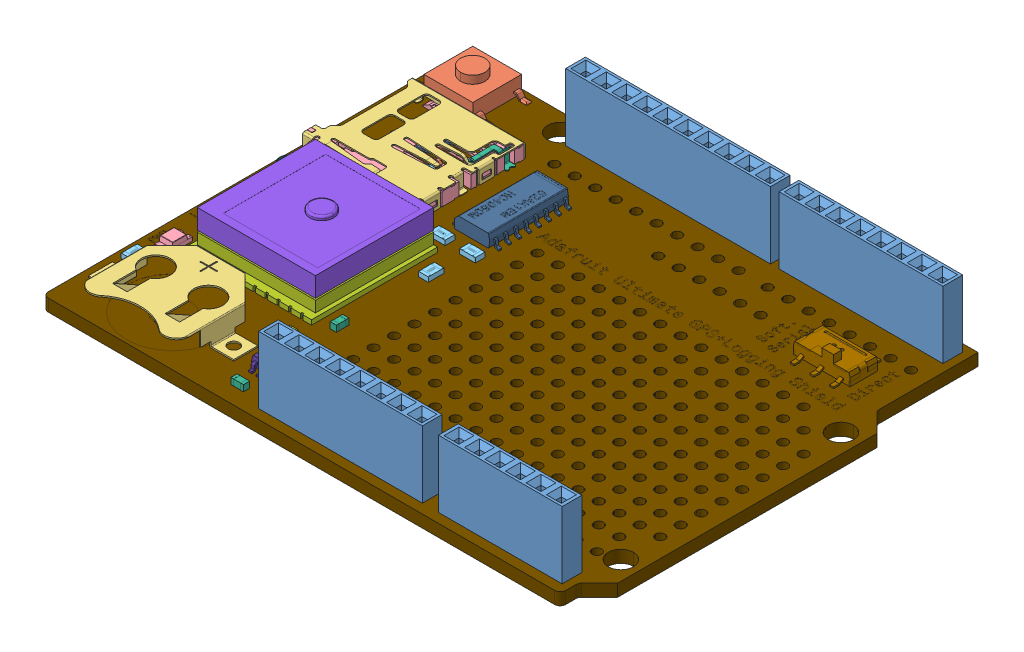
SolidWorks assembly Adafruit Ultimate GPS Logger Shield.stp, configuration Défaut. Lengths in mm.
Overall size (68.2 11.7 53.05).
43 component instances, 25 part files, 0 mates.
Components (placement in the parent):
- microSD_Connector.stp-1: microSD_Connector.stp [Défaut] at (-28.4341 1.764 56.1048) x (0 0 -1) z (1 0 0) size (14.11 1.91 15.46)
  - microSD_Pin_11.35.stp-1: microSD_Pin_11.35.stp [Défaut] at (1.325 0 -2) x (0 0 1) z (-1 0 0) size (7.35 1.15 0.63)
  - microSD_Pin_11.15.stp-1: microSD_Pin_11.15.stp [Défaut] at (2.425 0 -2) x (0 0 1) z (-1 0 0) size (7.35 1.15 0.62)
  - microSD_Pin_11.15.stp-2: microSD_Pin_11.15.stp [Défaut] at (-1.975 0 -2) x (0 0 1) z (-1 0 0) size (7.35 1.15 0.62)
  - microSD_Cover.stp-1: microSD_Cover.stp [Défaut] at (0 1.7 0) x (1 0 0) z (0 0 -1) size (13.96 1.91 15.21)
  - microSD_Pin_11.35.stp-2: microSD_Pin_11.35.stp [Défaut] at (3.525 0 -2) x (0 0 1) z (-1 0 0) size (7.35 1.15 0.63)
  - microSD_Body.stp-1: microSD_Body.stp [Défaut] at origin size (14.1 1.85 15.2)
  - microSD_Pin_10.75.stp-1: microSD_Pin_10.75.stp [Défaut] at (-0.875 0 -2) x (0 0 1) z (-1 0 0) size (7.25 1.15 0.62)
  - microSD_Pin_11.15.stp-3: microSD_Pin_11.15.stp [Défaut] at (4.625 0 -2) x (0 0 1) z (-1 0 0) size (7.35 1.15 0.62)
  - microSD_Card_Detect.stp-1: microSD_Card_Detect.stp [Défaut] at (4.99 -0.05 7.4) size (4.45 1.91 2.06)
  - microSD_Pin_11.15.stp-4: microSD_Pin_11.15.stp [Défaut] at (5.725 0 -2) x (0 0 1) z (-1 0 0) size (7.35 1.15 0.62)
  - microSD_Pin_11.15.stp-5: microSD_Pin_11.15.stp [Défaut] at (0.225 0 -2) x (0 0 1) z (-1 0 0) size (7.35 1.15 0.62)
- MODULO GPS_SMD.stp-1: MODULO GPS_SMD.stp [Défaut] at (-24.1111 1.764 72.4983) x (1 0 0) z (0 1 0) size (16 16 5.2)
  - FGPMMOPA6H_BASE.stp-1: FGPMMOPA6H_BASE.stp [Défaut] at origin size (16 16 2)
  - FGPMMOPA6H_TOP.stp-1: FGPMMOPA6H_TOP.stp [Défaut] at origin size (15 15 3)
- SLIDE SWITCH DPDT_SMD.stp-1: SLIDE SWITCH DPDT_SMD.stp [Défaut] at (17.6649 1.764 51.831) x (0 0 1) z (0 1 0) size (6 7.2 3)
  - SLIDE SWITCH.stp-1: SLIDE SWITCH.stp [Défaut] at origin size (6 7.2 3)
- 74HC4049_74HC4050.stp-1: 74HC4049_74HC4050.stp [Défaut] at (-15.3745 1.9423 51.4831) x (-1 0 0) z (0 1 0) size (5.85 10 1.8)
  - BODY.stp-1: BODY.stp [Défaut] at origin size (5.85 10 1.8)
- SW3dPS-UFL-R-SMD.stp-1: SW3dPS-UFL-R-SMD.stp [Défaut] at (-34.458 1.764 65.7075) x (0 0 1) z (0 1 0) size (3.4 3.1 1.25)
  - SW3dPS-UFL-R-SMD_Part_578.stp-1: SW3dPS-UFL-R-SMD_Part_578.stp [Défaut] at origin size (0.6 0.5 0.1)
  - SW3dPS-UFL-R-SMD_Part_525.stp-1: SW3dPS-UFL-R-SMD_Part_525.stp [Défaut] at origin size (3 2.6 0.35)
  - SW3dPS-UFL-R-SMD_Part_555.stp-1: SW3dPS-UFL-R-SMD_Part_555.stp [Défaut] at origin size (0.6 0.5 0.1)
  - SW3dPS-UFL-R-SMD_Part_562.stp-1: SW3dPS-UFL-R-SMD_Part_562.stp [Défaut] at origin size (0.4 1.8 0.1)
  - SW3dPS-UFL-R-SMD_Part_739.stp-1: SW3dPS-UFL-R-SMD_Part_739.stp [Défaut] at origin size (2.01 2 0.91)
  - SW3dPS-UFL-R-SMD_Part_540.stp-1: SW3dPS-UFL-R-SMD_Part_540.stp [Défaut] at origin size (0.4 1.8 0.1)
- MIC5225-3.3YM5.stp-1: MIC5225-3.3YM5.stp [Défaut] at (-12.2756 3.1697 88.6135) x (0 0 -1) z (0 1 0) size (3.05 3.05 1.3)
  - CHIP.stp-1: CHIP.stp [Défaut] at origin size (3.05 3.05 1.3)
- PCB Adafruit Ultimate GPS Logger Shield.stp-1: PCB Adafruit Ultimate GPS Logger Shield.stp [Défaut] at (-36.508 0.214 94.725) size (68.2 1.56 53.05)
- pins connection Shield.stp-1: pins connection Shield.stp [Défaut] at (-10.308 1.764 93.525) size (47.95 11.7 50.9)
- Buton.stp-1: Buton.stp [Défaut] at (-34.4592 1.764 48.375) size (9.48 3.1 6.2)
- SW3dPS-3002.stp-1: SW3dPS-3002.stp [Défaut] at (-26.3169 1.764 88.3628) x (-1 0 0) z (0 0 -1) size (18.44 2.78 12.04)
- LED SMD.stp-1: LED SMD.stp [Défaut] at (-33.7112 1.764 69.9441) x (0 0 -1) z (0 1 0) size (3.21 1.61 1.15)
- LED SMD.stp-2: LED SMD.stp [Défaut] at (-33.7112 1.764 75.4441) x (0 0 -1) z (0 1 0) size (3.21 1.61 1.15)
- LED SMD.stp-3: LED SMD.stp [Défaut] at (-33.7112 1.764 80.9441) x (0 0 -1) z (0 1 0) size (3.21 1.61 1.15)
- SMD RESISTOR-0805.stp-1: SMD RESISTOR-0805.stp [Défaut] at (-34.9121 2.064 84.7392) size (1.25 0.61 2)
- SMD RESISTOR-0805.stp-2: SMD RESISTOR-0805.stp [Défaut] at (-14.0292 2.064 67.8714) size (1.25 0.61 2)
- SMD RESISTOR-0805.stp-3: SMD RESISTOR-0805.stp [Défaut] at (-13.5461 2.064 63.138) x (0 0 -1) z (1 0 0) size (1.25 0.61 2)
- SMD RESISTOR-0805.stp-4: SMD RESISTOR-0805.stp [Défaut] at (-17.3775 2.064 63.138) x (0 0 -1) z (1 0 0) size (1.25 0.61 2)
- SMD CAPACITOR 0603.stp-1: SMD CAPACITOR 0603.stp [Défaut] at (-13.8958 2.164 92.2529) size (1.6 0.81 0.81)
- SMD CAPACITOR 0603.stp-2: SMD CAPACITOR 0603.stp [Défaut] at (-13.8958 2.164 85.2529) size (1.6 0.81 0.81)
- SMD CAPACITOR 0603.stp-3: SMD CAPACITOR 0603.stp [Défaut] at (-14.1323 2.164 79.4186) x (0 0 -1) z (1 0 0) size (1.6 0.81 0.81)
- SMD CAPACITOR 0402.stp-1: SMD CAPACITOR 0402.stp [Défaut] at (-16.4867 2.014 83.0672) size (1.01 0.51 0.51)
